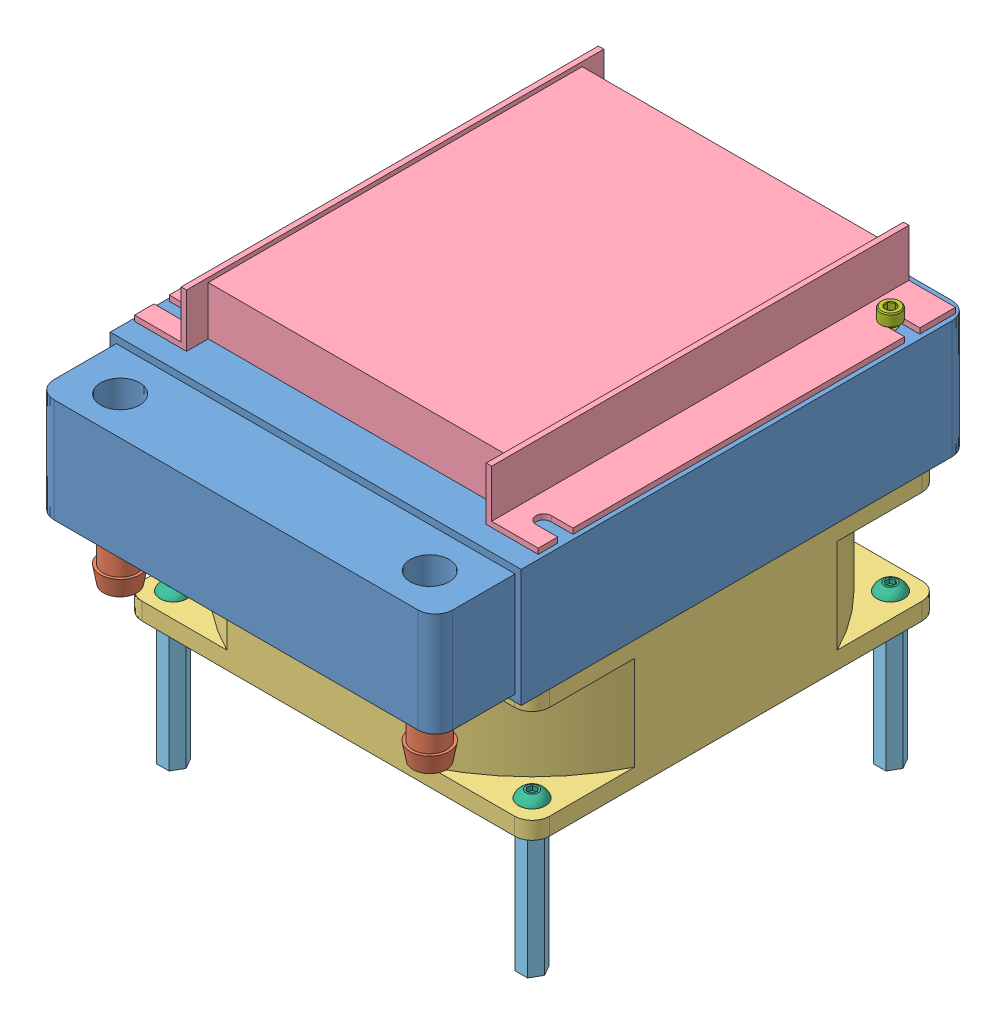
SolidWorks assembly Temperature Control Unit, configuration Default. Lengths in mm.
Overall size (120.4 125.95 155.49).
19 component instances, 7 part files, 47 mates.
Components (placement in the parent):
- temp_exchanger-1: temp_exchanger [Default] at (33.7843 2.8716 54.2914) size (120.4 34.54 154.69)
- G25_375_barb-1: G25_375_barb [Default] at (31.5319 1.8556 62.217) x (0.785955 0 -0.618284) z (0.618284 0 0.785955) size (17.16 22.56 18.29)
- G25_375_barb-2: G25_375_barb [Default] at (-62.8594 1.8556 101.7426) x (0.928427 0 0.371514) z (-0.371514 0 0.928427) size (17.16 22.56 18.29)
- 120mm_fan-1: 120mm_fan [Default] at (-100.7635 2.8716 -53.9513) x (0 0 -1) z (-1 0 0) size (119.38 37.75 119.38)
- Electric Heater-1: Electric Heater [Default] at (-108.8211 37.4156 60.098) size (118.27 15.56 122.24)
- S-008-150-STD-O-AL-001_8-32_standoff_f-f_p25hex-1: S-008-150-STD-O-AL-001_8-32_standoff_f-f_p25hex [Default] at (11.0865 -72.9784 -49.129) x (0.69212 0 -0.721782) z (0.721782 0 0.69212) size (7.12 38.1 7.04)
- S-008-038-BTN-H-SS-001-832x3_8-button-head-screw-1: S-008-038-BTN-H-SS-001-832x3_8-button-head-screw [Default] at (3.0977 -2.2034 -49.4395) x (-0.782671 0 -0.622435) z (-0.622435 0 0.782671) size (7.92 11.73 7.92)
- S-008-038-BTN-H-SS-001-832x3_8-button-head-screw-2: S-008-038-BTN-H-SS-001-832x3_8-button-head-screw [Default] at (3.0977 -29.8034 -49.4395) x (-0.995353 0 -0.096298) z (0.096298 0 -0.995353) size (7.92 11.73 7.92)
- S-008-038-BTN-H-SS-001-832x3_8-button-head-screw-5: S-008-038-BTN-H-SS-001-832x3_8-button-head-screw [Default] at (3.0977 -29.8034 55.5605) x (-0.95119 0 -0.308605) z (0.308605 0 -0.95119) size (7.92 11.73 7.92)
- S-008-038-BTN-H-SS-001-832x3_8-button-head-screw-7: S-008-038-BTN-H-SS-001-832x3_8-button-head-screw [Default] at (3.0977 -2.2034 55.5605) x (-0.999598 0 -0.028346) z (-0.028346 0 0.999598) size (7.92 11.73 7.92)
- S-008-038-BTN-H-SS-001-832x3_8-button-head-screw-10: S-008-038-BTN-H-SS-001-832x3_8-button-head-screw [Default] at (-101.9023 -2.2034 55.5605) x (-0.977449 0 0.211173) z (0.211173 0 0.977449) size (7.92 11.73 7.92)
- S-008-038-BTN-H-SS-001-832x3_8-button-head-screw-12: S-008-038-BTN-H-SS-001-832x3_8-button-head-screw [Default] at (-101.9023 -29.8034 55.5605) x (-0.525059 0 -0.851066) z (0.851066 0 -0.525059) size (7.92 11.73 7.92)
- S-008-038-BTN-H-SS-001-832x3_8-button-head-screw-14: S-008-038-BTN-H-SS-001-832x3_8-button-head-screw [Default] at (-101.9023 -29.8034 -49.4395) x (-0.35181 0 -0.936071) z (0.936071 0 -0.35181) size (7.92 11.73 7.92)
- S-008-038-BTN-H-SS-001-832x3_8-button-head-screw-17: S-008-038-BTN-H-SS-001-832x3_8-button-head-screw [Default] at (-101.9023 -2.2034 -49.4395) x (-0.711984 0 0.702196) z (0.702196 0 0.711984) size (7.92 11.73 7.92)
- S-008-150-STD-O-AL-001_8-32_standoff_f-f_p25hex-2: S-008-150-STD-O-AL-001_8-32_standoff_f-f_p25hex [Default] at (-93.9135 -72.9784 -49.129) x (0.69212 0 -0.721782) z (0.721782 0 0.69212) size (7.12 38.1 7.04)
- S-008-150-STD-O-AL-001_8-32_standoff_f-f_p25hex-3: S-008-150-STD-O-AL-001_8-32_standoff_f-f_p25hex [Default] at (11.0865 -72.9784 55.871) x (0.69212 0 -0.721782) z (0.721782 0 0.69212) size (7.12 38.1 7.04)
- S-008-150-STD-O-AL-001_8-32_standoff_f-f_p25hex-4: S-008-150-STD-O-AL-001_8-32_standoff_f-f_p25hex [Default] at (-93.9135 -72.9784 55.871) x (0.69212 0 -0.721782) z (0.721782 0 0.69212) size (7.12 38.1 7.04)
- 6-32_screw03-2: 6-32_screw03 [92196A145] at (3.0977 31.0656 -49.4395) x (-0.588308 0 -0.808637) z (0 -1 0) size (5.74 5.74 11.87)
- 6-32_screw03-3: 6-32_screw03 [92196A145] at (-101.9023 31.0656 -49.4395) x (-0.730159 0 -0.683278) z (0 -1 0) size (5.74 5.74 11.87)
Mates (geometry in assembly coordinates):
- Concentric1: concentric anti-aligned: cylinder of temp_exchanger-1 through (-4.3663 2.8716 78.0685) axis (0 1 0) radius 5.715; cylinder of G25_375_barb-1 through (-4.3663 9.8566 78.0685) axis (0 -1 0) radius 6.35
- Coincident1: coincident anti-aligned: plane of temp_exchanger-1 through (-107.8713 4.9036 89.7525) normal (0 -1 0); plane of G25_375_barb-1 through (31.5319 4.9036 62.217) normal (0 1 0)
- Coincident2: coincident anti-aligned: plane of temp_exchanger-1 through (-107.8713 4.9036 89.7525) normal (0 -1 0); plane of G25_375_barb-2 through (-62.8594 4.9036 101.7426) normal (0 1 0)
- Concentric2: concentric aligned: cylinder of temp_exchanger-1 through (-94.5363 2.8716 78.5796) axis (0 1 0) radius 5.715; cylinder of G25_375_barb-2 through (-94.5363 4.7766 78.5796) axis (0 1 0) radius 4.953
- Parallel1: parallel anti-aligned: plane of temp_exchanger-1 through (-109.6493 37.4156 66.3845) normal (0 0 1); plane of G25_375_barb-1 through (0.253 4.9036 70.0675) normal (0 0 -1)
- Parallel2: parallel anti-aligned: plane of temp_exchanger-1 through (-109.6493 37.4156 66.3845) normal (0 0 1); plane of G25_375_barb-2 through (-89.917 4.9036 70.5786) normal (0 0 -1)
- Concentric3: concentric anti-aligned: circle of temp_exchanger-1; cylinder of 120mm_fan-1 through (3.0977 2.8716 -49.4395) axis (0 -1 0) radius 2.286
- Coincident5: coincident anti-aligned: plane of temp_exchanger-1 through (33.7843 2.8716 54.2914) normal (0 -1 0); plane of 120mm_fan-1 through (-100.7635 2.8716 -53.9513) normal (0 1 0)
- Concentric5: concentric aligned: cylinder of temp_exchanger-1 through (3.0977 2.8716 -49.4395) axis (0 1 0) radius 1.397; cylinder of Electric Heater-1 through (3.0977 37.4156 -49.4395) axis (0 1 0) radius 2.2479
- Parallel4: parallel aligned: plane of temp_exchanger-1 through (-109.6493 37.4156 -64.9335) normal (-1 0 0); plane of Electric Heater-1 through (-108.8211 39.0031 60.098) normal (-1 0 0)
- Coincident7: coincident anti-aligned: plane of temp_exchanger-1 through (33.7843 37.4156 54.2914) normal (0 1 0); plane of Electric Heater-1 through (-108.8211 37.4156 60.098) normal (0 -1 0)
- Coincident8: coincident anti-aligned: plane of 120mm_fan-1 through (-100.7635 -34.8784 -53.9513) normal (0 -1 0); plane of S-008-150-STD-O-AL-001_8-32_standoff_f-f_p25hex-1 through (11.0865 -34.8784 -49.129) normal (0 1 0)
- Concentric6: concentric anti-aligned: cylinder of 120mm_fan-1 through (3.0977 2.8716 -49.4395) axis (0 -1 0) radius 2.286; cylinder of S-008-150-STD-O-AL-001_8-32_standoff_f-f_p25hex-1 through (3.0977 -44.4034 -49.4395) axis (0 1 0) radius 1.7272
- Parallel5: parallel aligned: plane of 120mm_fan-1 through (10.2877 -34.8784 -56.6295) normal (0 0 -1); plane of S-008-150-STD-O-AL-001_8-32_standoff_f-f_p25hex-1 through (4.9308 -34.8784 -52.6145) normal (0 0 -1)
- Concentric7: concentric anti-aligned: cylinder of 120mm_fan-1 through (3.0977 2.8716 -49.4395) axis (0 -1 0) radius 2.286; cylinder of S-008-038-BTN-H-SS-001-832x3_8-button-head-screw-1 through (3.0977 7.3216 -49.4395) axis (0 1 0) radius 2.0828
- Coincident10: coincident anti-aligned: plane of 120mm_fan-1 through (-49.4023 -2.2034 3.0605) normal (0 -1 0); plane of S-008-038-BTN-H-SS-001-832x3_8-button-head-screw-1 through (4.7278 -2.2034 -48.143) normal (0 1 0)
- Concentric8: concentric aligned: cylinder of 120mm_fan-1 through (3.0977 2.8716 -49.4395) axis (0 -1 0) radius 2.286; cylinder of S-008-038-BTN-H-SS-001-832x3_8-button-head-screw-2 through (3.0977 -39.3284 -49.4395) axis (0 -1 0) radius 2.0828
- Coincident11: coincident anti-aligned: plane of 120mm_fan-1 through (-49.4023 -29.8034 3.0605) normal (0 1 0); plane of S-008-038-BTN-H-SS-001-832x3_8-button-head-screw-2 through (5.1708 -29.8034 -49.2389) normal (0 -1 0)
- Concentric9: concentric aligned: cylinder of 120mm_fan-1 through (3.0977 2.8716 55.5605) axis (0 -1 0) radius 2.286; cylinder of S-008-038-BTN-H-SS-001-832x3_8-button-head-screw-5 through (3.0977 -39.3284 55.5605) axis (0 -1 0) radius 2.0828
- Coincident12: coincident anti-aligned: plane of 120mm_fan-1 through (-49.4023 -29.8034 3.0605) normal (0 1 0); plane of S-008-038-BTN-H-SS-001-832x3_8-button-head-screw-5 through (5.0788 -29.8034 56.2033) normal (0 -1 0)
- Concentric10: concentric anti-aligned: cylinder of 120mm_fan-1 through (3.0977 2.8716 55.5605) axis (0 -1 0) radius 2.286; cylinder of S-008-038-BTN-H-SS-001-832x3_8-button-head-screw-7 through (3.0977 7.3216 55.5605) axis (0 1 0) radius 2.0828
- Coincident13: coincident anti-aligned: plane of 120mm_fan-1 through (-49.4023 -2.2034 3.0605) normal (0 -1 0); plane of S-008-038-BTN-H-SS-001-832x3_8-button-head-screw-7 through (5.1796 -2.2034 55.6196) normal (0 1 0)
- Concentric11: concentric anti-aligned: cylinder of 120mm_fan-1 through (-101.9023 2.8716 55.5605) axis (0 -1 0) radius 2.286; cylinder of S-008-038-BTN-H-SS-001-832x3_8-button-head-screw-10 through (-101.9023 7.3216 55.5605) axis (0 1 0) radius 2.0828
- Coincident14: coincident anti-aligned: plane of 120mm_fan-1 through (-49.4023 -2.2034 3.0605) normal (0 -1 0); plane of S-008-038-BTN-H-SS-001-832x3_8-button-head-screw-10 through (-99.8665 -2.2034 55.1207) normal (0 1 0)
- Concentric12: concentric aligned: cylinder of 120mm_fan-1 through (-101.9023 2.8716 55.5605) axis (0 -1 0) radius 2.286; cylinder of S-008-038-BTN-H-SS-001-832x3_8-button-head-screw-12 through (-101.9023 -39.3284 55.5605) axis (0 -1 0) radius 2.0828
- Coincident15: coincident anti-aligned: plane of 120mm_fan-1 through (-49.4023 -29.8034 3.0605) normal (0 1 0); plane of S-008-038-BTN-H-SS-001-832x3_8-button-head-screw-12 through (-100.8087 -29.8034 57.3331) normal (0 -1 0)
- Concentric13: concentric aligned: cylinder of 120mm_fan-1 through (-101.9023 2.8716 -49.4395) axis (0 -1 0) radius 2.286; cylinder of S-008-038-BTN-H-SS-001-832x3_8-button-head-screw-14 through (-101.9023 -39.3284 -49.4395) axis (0 -1 0) radius 2.0828
- Coincident16: coincident anti-aligned: plane of 120mm_fan-1 through (-49.4023 -29.8034 3.0605) normal (0 1 0); plane of S-008-038-BTN-H-SS-001-832x3_8-button-head-screw-14 through (-101.1696 -29.8034 -47.4898) normal (0 -1 0)
- Concentric14: concentric anti-aligned: cylinder of 120mm_fan-1 through (-101.9023 2.8716 -49.4395) axis (0 -1 0) radius 2.286; cylinder of S-008-038-BTN-H-SS-001-832x3_8-button-head-screw-17 through (-101.9023 7.3216 -49.4395) axis (0 1 0) radius 2.0828
- Coincident17: coincident anti-aligned: plane of 120mm_fan-1 through (-49.4023 -2.2034 3.0605) normal (0 -1 0); plane of S-008-038-BTN-H-SS-001-832x3_8-button-head-screw-17 through (-100.4194 -2.2034 -50.902) normal (0 1 0)
- Coincident18: coincident anti-aligned: plane of 120mm_fan-1 through (-100.7635 -34.8784 -53.9513) normal (0 -1 0); plane of S-008-150-STD-O-AL-001_8-32_standoff_f-f_p25hex-2 through (-93.9135 -34.8784 -49.129) normal (0 1 0)
- Concentric15: concentric anti-aligned: cylinder of S-008-038-BTN-H-SS-001-832x3_8-button-head-screw-14 through (-101.9023 -39.3284 -49.4395) axis (0 -1 0) radius 2.0828; cylinder of S-008-150-STD-O-AL-001_8-32_standoff_f-f_p25hex-2 through (-101.9023 -44.4034 -49.4395) axis (0 1 0) radius 1.7272
- Parallel6: parallel aligned: plane of 120mm_fan-1 through (10.2877 -34.8784 -56.6295) normal (0 0 -1); plane of S-008-150-STD-O-AL-001_8-32_standoff_f-f_p25hex-2 through (-100.0692 -34.8784 -52.6145) normal (0 0 -1)
- Coincident19: coincident anti-aligned: plane of 120mm_fan-1 through (-100.7635 -34.8784 -53.9513) normal (0 -1 0); plane of S-008-150-STD-O-AL-001_8-32_standoff_f-f_p25hex-3 through (11.0865 -34.8784 55.871) normal (0 1 0)
- Parallel7: parallel aligned: plane of 120mm_fan-1 through (10.2877 -34.8784 -56.6295) normal (0 0 -1); plane of S-008-150-STD-O-AL-001_8-32_standoff_f-f_p25hex-3 through (4.9308 -34.8784 52.3855) normal (0 0 -1)
- Concentric16: concentric anti-aligned: cylinder of S-008-038-BTN-H-SS-001-832x3_8-button-head-screw-5 through (3.0977 -39.3284 55.5605) axis (0 -1 0) radius 2.0828; cylinder of S-008-150-STD-O-AL-001_8-32_standoff_f-f_p25hex-3 through (3.0977 -44.4034 55.5605) axis (0 1 0) radius 1.7272
- Coincident20: coincident anti-aligned: plane of 120mm_fan-1 through (-100.7635 -34.8784 -53.9513) normal (0 -1 0); plane of S-008-150-STD-O-AL-001_8-32_standoff_f-f_p25hex-4 through (-93.9135 -34.8784 55.871) normal (0 1 0)
- Parallel8: parallel aligned: plane of 120mm_fan-1 through (10.2877 -34.8784 -56.6295) normal (0 0 -1); plane of S-008-150-STD-O-AL-001_8-32_standoff_f-f_p25hex-4 through (-100.0692 -34.8784 52.3855) normal (0 0 -1)
- Concentric17: concentric anti-aligned: cylinder of S-008-038-BTN-H-SS-001-832x3_8-button-head-screw-12 through (-101.9023 -39.3284 55.5605) axis (0 -1 0) radius 2.0828; cylinder of S-008-150-STD-O-AL-001_8-32_standoff_f-f_p25hex-4 through (-101.9023 -44.4034 55.5605) axis (0 1 0) radius 1.7272
- Concentric18: concentric aligned: cylinder of temp_exchanger-1 through (-101.9023 2.8716 -49.4395) axis (0 1 0) radius 1.397; cylinder of ? through (-101.9023 40.5906 -49.4395) axis (0 1 0) radius 1.8986
- Coincident21: coincident anti-aligned: plane of Electric Heater-1 through (-108.9191 39.0031 60.098) normal (0 1 0); plane of ? through (-116.5073 39.0031 56.9567) normal (0 -1 0)
- Parallel9: parallel aligned: plane of temp_exchanger-1 through (-109.6493 37.4156 -64.9335) normal (-1 0 0); plane of ? through (-116.5073 39.0031 56.9567) normal (-1 0 0)
- Concentric19: concentric anti-aligned: cylinder of temp_exchanger-1 through (3.0977 2.8716 -49.4395) axis (0 1 0) radius 1.397; cylinder of 6-32_screw03-2 through (3.0977 42.5083 -49.4395) axis (0 -1 0) radius 2.8702
- Coincident22: coincident anti-aligned: plane of Electric Heater-1 through (-108.8211 39.0031 60.098) normal (0 1 0); plane of 6-32_screw03-2 through (3.0977 39.0031 -49.4395) normal (0 -1 0)
- Concentric20: concentric anti-aligned: cylinder of temp_exchanger-1 through (-101.9023 2.8716 -49.4395) axis (0 1 0) radius 1.397; cylinder of 6-32_screw03-3 through (-101.9023 42.5083 -49.4395) axis (0 -1 0) radius 2.8702
- Coincident23: coincident anti-aligned: plane of Electric Heater-1 through (-108.8211 39.0031 60.098) normal (0 1 0); plane of 6-32_screw03-3 through (-101.9023 39.0031 -49.4395) normal (0 -1 0)
- Concentric23: concentric anti-aligned: cylinder of temp_exchanger-1 through (-101.9023 2.8716 55.5605) axis (0 1 0) radius 1.397; cylinder of 120mm_fan-1 through (-101.9023 2.8716 55.5605) axis (0 -1 0) radius 2.286
